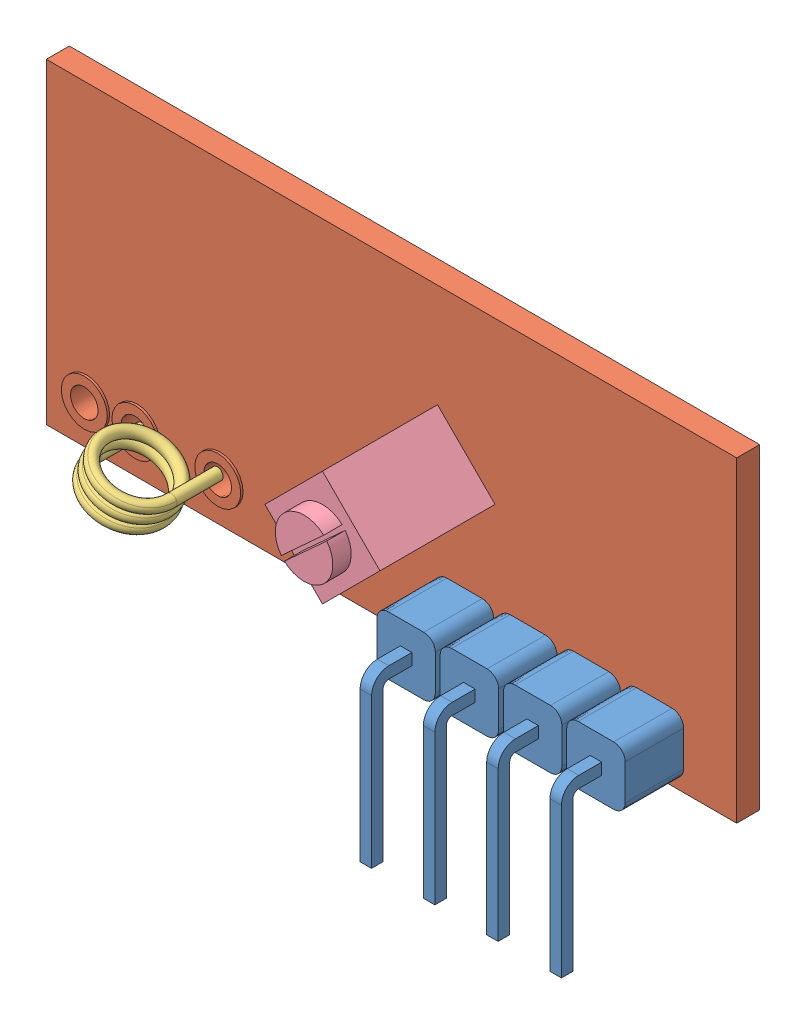
SolidWorks assembly 433MhzRX v4.step, configuration Défaut. Lengths in mm.
Overall size (30 19.01 6.8).
9 component instances, 4 part files, 0 mates.
Components (placement in the parent):
- 433 OOK Receiver.step-1: 433 OOK Receiver.step [Défaut] at origin size (30 19.01 6.8)
  - Pin Headers.step-1: Pin Headers.step [Défaut] at origin size (10.79 8.27 4.29)
    - Pin Header Bendt.step-1: Pin Header Bendt.step [Défaut] at (-0.55 -6.5006 0.0858) x (1 0 0) z (0 -1 0) size (2.54 4.29 8.27)
    - Pin Header Bendt.step-2: Pin Header Bendt.step [Défaut] at (-3.3 -6.5006 0.0858) x (1 0 0) z (0 -1 0) size (2.54 4.29 8.27)
    - Pin Header Bendt.step-3: Pin Header Bendt.step [Défaut] at (-6.05 -6.5006 0.0858) x (1 0 0) z (0 -1 0) size (2.54 4.29 8.27)
    - Pin Header Bendt.step-4: Pin Header Bendt.step [Défaut] at (-8.8 -6.5006 0.0858) x (1 0 0) z (0 -1 0) size (2.54 4.29 8.27)
  - pcb.step-1: pcb.step [Défaut] at origin size (30 13.75 1.1)
  - small coil v1.step-1: small coil v1.step [Défaut] at (-21.2443 -21.3088 -0.1406) x (0.939693 0.34202 0) z (0.34202 -0.939693 0) size (3.59 4.14 3.27)
  - Frequency Selector.step-1: Frequency Selector.step [Défaut] at origin size (5 5 5.8)
